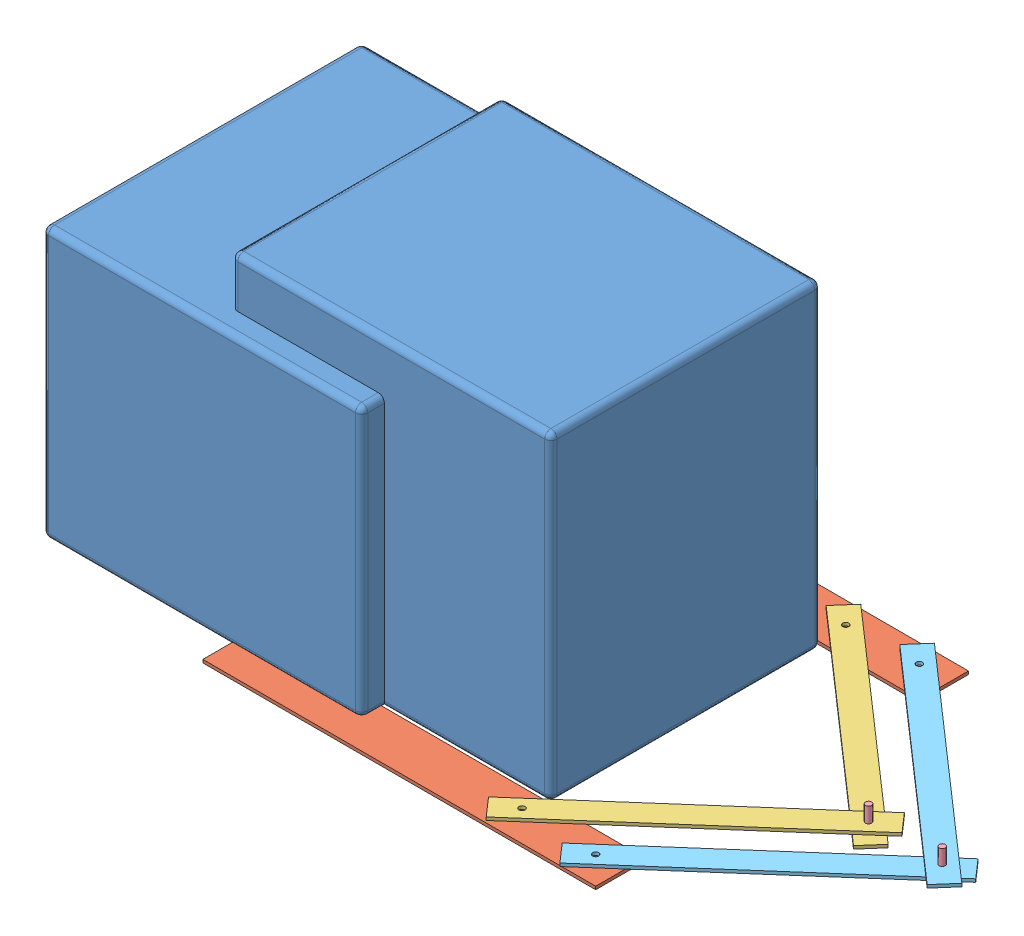
SolidWorks assembly Test_Assem, configuration Default. Lengths in mm.
Overall size (795.35 330.2 387.4).
10 component instances, 5 part files, 21 mates.
Components (placement in the parent):
- Power_Cube-1: Power_Cube [Default] at (366.9869 0 353.75) x (-1 0 0) z (0 -1 0) size (330.2 279.4 330.2)
- Test_Arm-1: Test_Arm [Default] at (60.4097 0 72.4012) size (406.4 3.17 50.8)
- Test_Arm-2: Test_Arm [Default] at (60.4097 0 407.2202) size (406.4 3.17 50.8)
- Test_Arm2-1: Test_Arm2 [Default] at (337.7369 3.175 39.8114) x (0.752062 0 0.659093) z (-0.659093 0 0.752062) size (304.8 3.17 25.4)
- Test_Arm2-2: Test_Arm2 [Default] at (354.4778 6.35 408.1124) x (0.752062 0 -0.659093) z (0.659093 0 0.752062) size (304.8 3.17 25.4)
- Test_Pin-1: Test_Pin [Default] at (556.2334 0 214.4107) size (6.35 25.4 6.35)
- Test_Arm3-1: Test_Arm3 [Default] at (430.6778 3.175 408.1124) x (0.752062 0 -0.659093) z (0.659093 0 0.752062) size (304.8 3.17 25.4)
- Test_Pin-2: Test_Pin [Default] at (632.4334 0 214.4107) x (0.242918 0 0.970047) z (-0.970047 0 0.242918) size (6.35 25.4 6.35)
- Test_Arm3-2: Test_Arm3 [Default] at (659.9063 6.35 221.6005) x (-0.752062 0 -0.659093) z (0.659093 0 -0.752062) size (304.8 3.17 25.4)
- Power_Cube-2: Power_Cube [Default] at (194.7542 279.4 377.2935) x (-1 0 0) z (0 0 1) size (330.2 279.4 330.2)
Mates (geometry in assembly coordinates):
- Coincident4: coincident aligned: plane of Test_Arm-1 through (60.4097 3.175 72.4012) normal (0 1 0); plane of Test_Arm-2 through (60.4097 3.175 407.2202) normal (0 1 0)
- Coincident6: coincident anti-aligned: plane of Test_Arm-1 through (60.4097 3.175 72.4012) normal (0 1 0); plane of Test_Arm2-1 through (337.7369 3.175 39.8114) normal (0 -1 0)
- Concentric1: concentric aligned: circle of Test_Arm-1; circle of Test_Arm2-1
- Coincident8: coincident anti-aligned: plane of Test_Arm2-1 through (337.7369 6.35 39.8114) normal (0 1 0); plane of Test_Arm2-2 through (354.4778 6.35 408.1124) normal (0 -1 0)
- Concentric2: concentric aligned: circle of Test_Arm-2; circle of Test_Arm2-2
- Concentric3: concentric aligned: circle of Test_Arm2-1; circle of Test_Arm2-2
- Coincident11: coincident anti-aligned: plane of Test_Arm-1 through (60.4097 0 72.4012) normal (0 -1 0); plane of assembly through (0 0 0) normal (0 1 0)
- Coincident12: coincident aligned: plane of Test_Pin-1 through (556.2334 0 214.4107) normal (0 1 0); plane of assembly through (0 0 0) normal (0 1 0)
- Concentric4: concentric aligned: circle of Test_Arm2-2; circle of Test_Pin-1
- Coincident14: coincident anti-aligned: plane of Test_Arm-2 through (60.4097 3.175 407.2202) normal (0 1 0); plane of Test_Arm3-1 through (430.6778 3.175 408.1124) normal (0 -1 0)
- Concentric5: concentric aligned: circle of Test_Arm-2; circle of Test_Arm3-1
- Parallel1: parallel aligned: plane of Test_Pin-2 through (632.4334 0 214.4107) normal (0 1 0); plane of assembly through (0 0 0) normal (0 1 0)
- Coincident21: coincident aligned: plane of Test_Pin-2 through (632.4334 0 214.4107) normal (0 1 0); plane of assembly through (0 0 0) normal (0 1 0)
- Concentric9: concentric aligned: circle of Test_Arm-1; circle of Test_Arm3-2
- Concentric10: concentric aligned: circle of Test_Pin-2; circle of Test_Arm3-2
- Concentric13: concentric aligned: circle of Test_Arm3-1; circle of Test_Pin-2
- Coincident29: coincident aligned: plane of Test_Arm-1 through (60.4097 3.175 72.4012) normal (-1 0 0); plane of Test_Arm-2 through (60.4097 3.175 407.2202) normal (-1 0 0)
- Coincident30: coincident anti-aligned: plane of Test_Arm3-1 through (430.6778 6.35 408.1124) normal (0 1 0); plane of Test_Arm3-2 through (659.9063 6.35 221.6005) normal (0 -1 0)
- Coincident31: coincident anti-aligned: plane of Power_Cube-1 through (366.9869 0 74.35) normal (0 -1 0); plane of assembly through (0 0 0) normal (0 1 0)
- Parallel6: parallel anti-aligned: plane of Power_Cube-1 through (366.9869 0 74.35) normal (0 0 -1); plane of assembly through (0 0 0) normal (0 0 1)
- Coincident33: coincident anti-aligned: plane of Power_Cube-2 through (194.7542 0 377.2935) normal (0 -1 0); plane of assembly through (0 0 0) normal (0 1 0)
